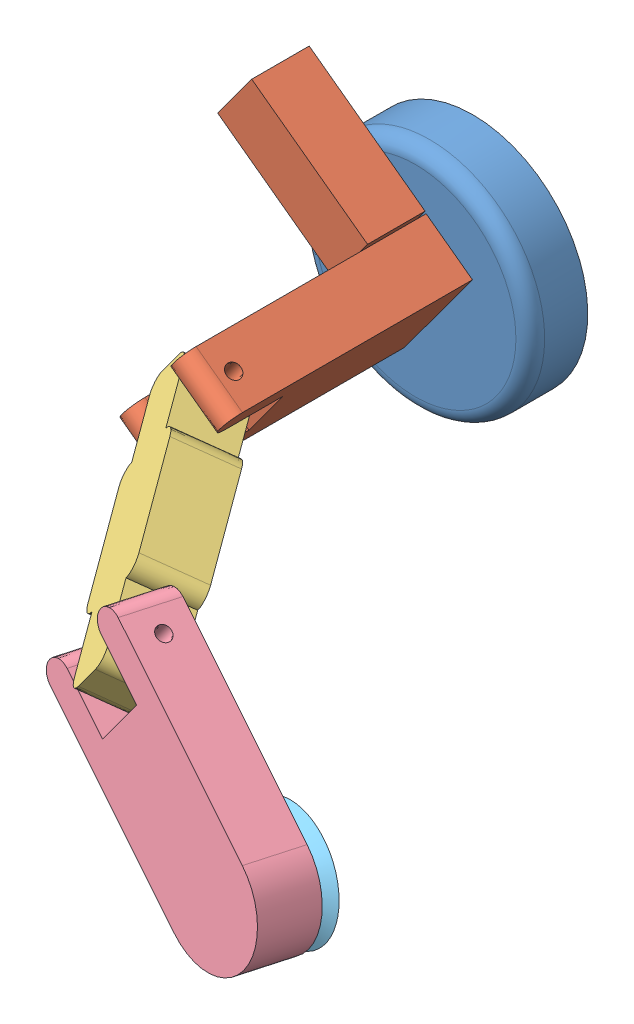
SolidWorks assembly Assem1, configuration Default. Lengths in mm.
Overall size (1779.98 1782.81 2071.15).
5 component instances, 5 part files, 8 mates.
Components (placement in the parent):
- base v4.step-1: base v4.step [Default] at (-433.4053 -847.2607 238.6879) x (0 1 0) z (0 0 1) size (800 800 200)
- Link 1 v11.step-2: Link 1 v11.step [Default] at (-315.0227 -686.0603 438.6879) x (0.806002 -0.591913 0) z (-0.591913 -0.806002 0) size (706.44 900 402.59)
- Link 2 v10.step-1: Link 2 v10.step [Default] at (-243.9197 -1172.5192 1642.2318) x (0.641328 -0.47098 -0.605703) z (0.591913 0.806002 0) size (200 950 300)
- Link 3 v6.step-1: Link 3 v6.step [Default] at (328.5015 -1158.6527 1874.5768) x (0.142087 -0.104346 -0.984339) z (-0.591913 -0.806002 0) size (200 950 400)
- Vacuum Gripper v6.step-1: Vacuum Gripper v6.step [Default] at (469.1615 -1510.0892 1781.7805) x (0.447852 0.893601 -0.030081) z (-0.142087 0.104346 0.984339) size (399.92 399.92 168.11)
Mates (geometry in assembly coordinates):
- Coincident3: coincident anti-aligned: plane of base v4.step-1 through (-433.4053 -847.2607 388.6879) normal (0 0 1); plane of Link 1 v11.step-2 through (-433.4053 -847.2607 388.6879) normal (0 0 -1)
- Concentric5: concentric aligned: cylinder of base v4.step-1 through (-433.4053 -847.2607 438.6879) axis (0 0 -1) radius 100; cylinder of Link 1 v11.step-2 through (-433.4053 -847.2607 438.6879) axis (0 0 -1) radius 100
- Coincident9: coincident anti-aligned: plane of Link 1 v11.step-2 through (-492.5966 -927.8609 1038.6879) normal (0.591913 0.806002 0); plane of Link 2 v10.step-1 through (-409.603 -988.8098 1323.9554) normal (-0.591913 -0.806002 0)
- Concentric8: concentric aligned: cylinder of Link 1 v11.step-2 through (-492.5966 -927.8609 1188.6879) axis (-0.591913 -0.806002 0) radius 25; cylinder of Link 2 v10.step-1 through (-374.214 -766.6605 1188.6879) axis (-0.591913 -0.806002 0) radius 25
- Coincident10: coincident anti-aligned: plane of Link 2 v10.step-1 through (-71.5316 -988.9449 1682.0164) normal (0.591913 0.806002 0); plane of Link 3 v6.step-1 through (110.6344 -1122.7243 1839.3196) normal (-0.591913 -0.806002 0)
- Concentric9: concentric anti-aligned: cylinder of Link 2 v10.step-1 through (11.462 -1049.8939 1817.2838) axis (-0.591913 -0.806002 0) radius 25; cylinder of Link 3 v6.step-1 through (11.462 -1049.8939 1817.2838) axis (0.591913 0.806002 0) radius 25
- Coincident12: coincident anti-aligned: plane of Link 3 v6.step-1 through (244.1621 -1344.8537 1780.5501) normal (0.142087 -0.104346 -0.984339); circle of Vacuum Gripper v6.step-1
- Concentric10: concentric aligned: cylinder of Link 3 v6.step-1 through (462.3413 -1505.0806 1829.0288) axis (-0.142087 0.104346 0.984339) radius 25; cylinder of Vacuum Gripper v6.step-1 through (460.0679 -1503.411 1844.7782) axis (-0.142087 0.104346 0.984339) radius 25
